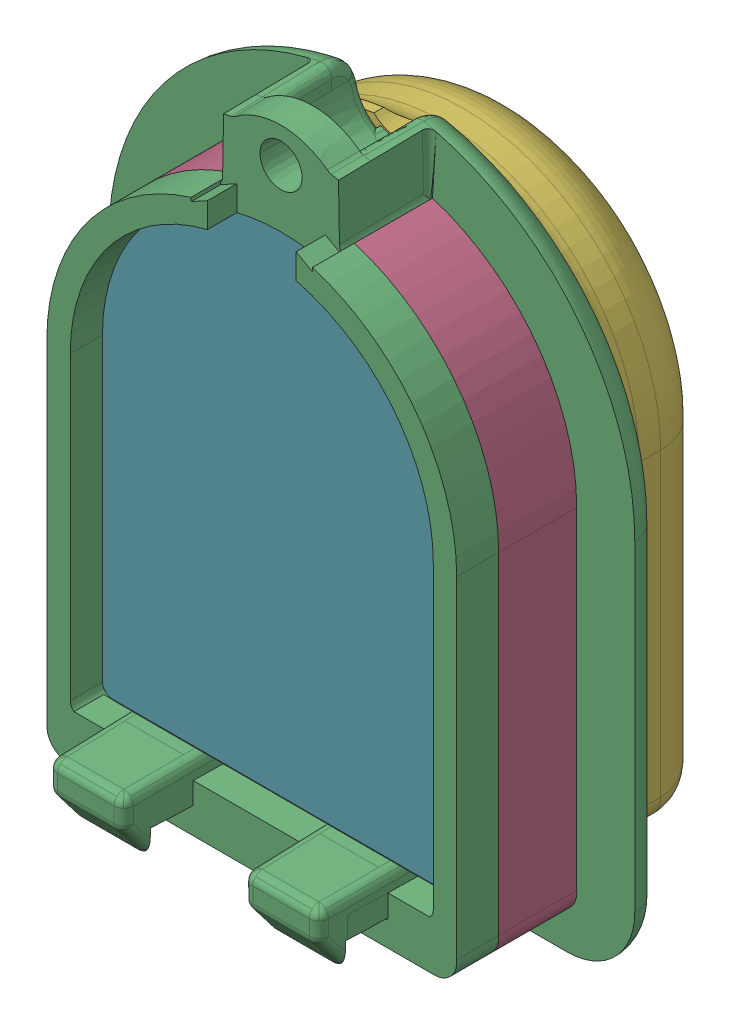
SolidWorks assembly Coord, configuration 默认. Lengths in mm.
Overall size (26.95 34.26 17.16).
6 component instances, 6 part files, 15 mates.
Components (placement in the parent):
- CoordOriginBody-1: CoordOriginBody [默认] at (-2.213 7.3799 -8.324) size (26.95 34.26 11.18)
- CoordTransBody-1: CoordTransBody [默认] at (-2.213 7.3799 -8.324) size (21.01 28.27 4)
- CoordInsideSKin-1: CoordInsideSKin [默认] at (-2.213 4.0799 -8.324) x (-1 0 0) z (0 0 -1) size (18.6 25.2 5.2)
- CoordoutSkin-1: CoordoutSkin [默认] at (-2.213 4.0799 -8.324) x (-1 0 0) z (0 0 -1) size (21.8 28.5 6)
- CoordLens-1: CoordLens [默认] at (-2.213 7.3799 -8.324) size (18.6 25.2 6)
- CoordMarker-1: CoordMarker [默认] at (0.7621 0.6661 -13.524) size (15.6 21.6 1.5) (hidden)
Mates (geometry in assembly coordinates):
- 重合1: coincident anti-aligned: plane of OriginBody-1 through (-2.213 7.3799 -6.824) normal (0 0 1); plane of 实体3-1 through (7.137 -9.7124 -6.824) normal (0 0 -1)
- 同心1: concentric aligned: cylinder of OriginBody-1 through (-2.213 7.3799 -0.674) axis (0 0 -1) radius 10.5; cylinder of 实体3-1 through (-2.213 7.3799 -0.674) axis (0 0 -1) radius 10.5
- 重合2: coincident aligned: plane of OriginBody-1 through (8.287 7.3799 -0.674) normal (1 0 0); plane of 实体3-1 through (8.287 7.3799 -0.674) normal (1 0 0)
- 重合3: coincident anti-aligned: plane of 实体3-1 through (-2.213 -8.5201 48.523) normal (0 1 0); plane of NewBoardlensnew-1 through (-11.513 -8.5201 -2.324) normal (0 -1 0)
- 同心2: concentric aligned: cylinder of 实体3-1 through (-2.213 7.3799 48.523) axis (0 0 -1) radius 9.3; cylinder of NewBoardlensnew-1 through (-2.213 7.3799 -2.324) axis (0 0 -1) radius 9.3
- 重合4: coincident aligned: plane of OriginBody-1 through (-2.2735 3.9424 -8.324) normal (0 0 -1); plane of NewBoardlensnew-1 through (-2.213 7.3799 -8.324) normal (0 0 -1)
- 重合5: coincident anti-aligned: plane of NewInsideSkin-1 through (-11.013 -8.0201 -8.324) normal (0 0 1); plane of NewBoardlensnew-1 through (-2.213 7.3799 -8.324) normal (0 0 -1)
- 平行1: parallel anti-aligned: line of OriginBody-1 through (-11.513 7.3799 -8.324) axis (0 -1 0); line of NewInsideSkin-1 through (-11.513 -8.0201 -8.324) axis (0 1 0)
- 同心3: concentric anti-aligned: circle of OriginBody-1; circle of NewInsideSkin-1
- 重合6: coincident anti-aligned: plane of NewInsideSkin-1 through (-11.013 -8.0201 -13.524) normal (0 0 -1); plane of outSkin-1 through (-11.013 -8.0201 -13.524) normal (0 0 1)
- 同心4: concentric aligned: cylinder of NewInsideSkin-1 through (-2.213 7.3799 -13.524) axis (0 0 1) radius 9.3; cylinder of outSkin-1 through (-2.213 7.3799 -13.524) axis (0 0 1) radius 9.3
- 平行2: parallel aligned: plane of NewInsideSkin-1 through (-11.013 -8.5201 -13.524) normal (0 -1 0); plane of outSkin-1 through (-11.013 -9.3201 -13.524) normal (0 -1 0)
- 重合8: coincident aligned: plane of CoordInsideSKin-1 through (-11.013 -8.0201 -13.524) normal (0 0 -1); plane of CoordMarker-1 through (-9.213 3.7299 -13.524) normal (0 0 -1)
- 宽度1: width aligned: plane of CoordInsideSKin-1 through (7.087 -8.0201 -13.524) normal (1 0 0); plane of CoordMarker-1 through (-11.513 7.3799 -13.524) normal (-1 0 0); plane of CoordInsideSKin-1 through (5.587 -0.2701 -12.774) normal (1 0 0); plane of CoordMarker-1 through (-10.013 1.7299 -12.774) normal (-1 0 0)
- 相切2: tangent: line of CoordInsideSKin-1 through (5.087 -6.5201 -13.524) axis (-1 0 0); cylinder of CoordMarker-1 through (4.787 -6.2701 -12.024) axis (0 0 -1) radius 0.25
